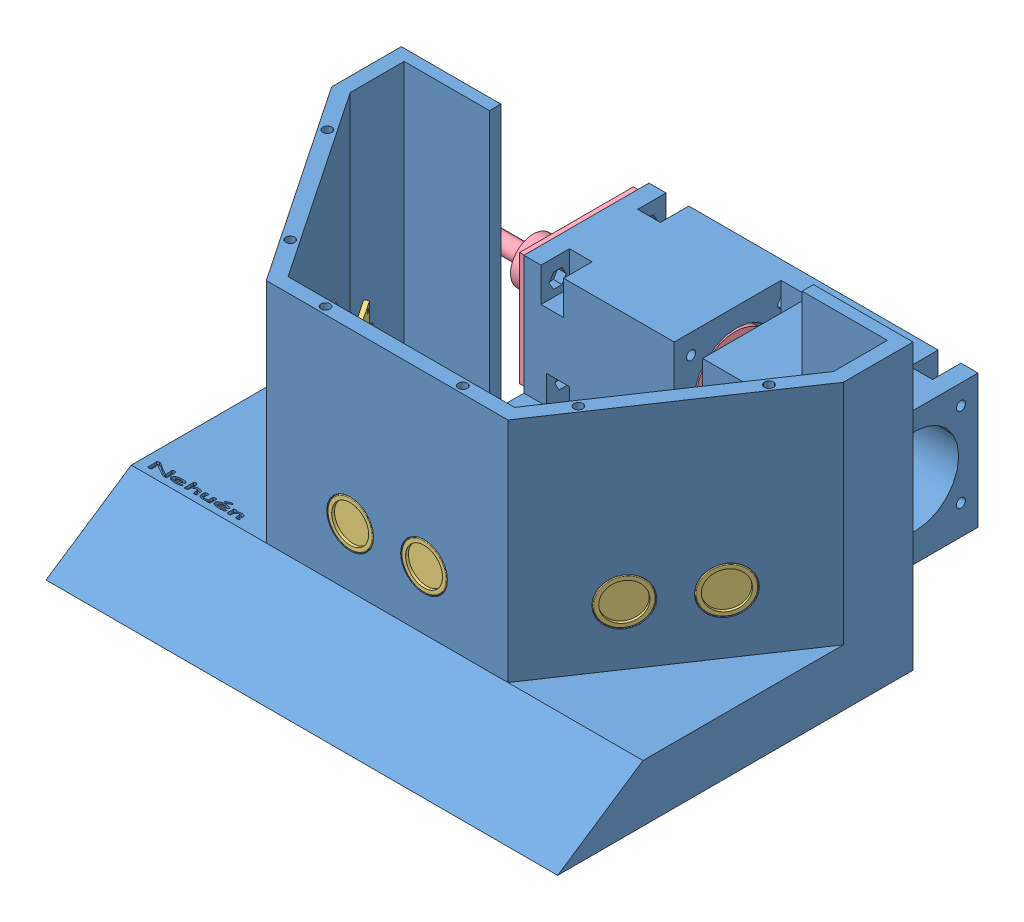
SolidWorks assembly Assem del sumo 2.0, configuration Default. Lengths in mm.
Overall size (186.62 100 180).
7 component instances, 4 part files, 13 mates.
Components (placement in the parent):
- SUMO 3.0-1: SUMO 3.0 [Default] at (66.1854 100.2215 134.4233) size (180 100 180)
- CNY70.step-1: CNY70.step [Default] at (7.7782 59.346 269.6233) x (1 0 0) z (0 0 -1) size (7 11.75 7)
- Sensor ultrasonico (1).step-1: Sensor ultrasonico (1).step [Default] at (79.2782 93.946 270.9233) x (-1 0 0) z (0 0 1) size (45 26.6 18)
- Sensor ultrasonico (1).step-2: Sensor ultrasonico (1).step [Default] at (134.3329 93.946 241.6345) x (-0.558824 0 0.829287) z (0.829287 0 0.558824) size (45 26.6 18)
- Sensor ultrasonico (1).step-3: Sensor ultrasonico (1).step [Default] at (24.2236 93.946 241.6345) x (-0.558824 0 -0.829287) z (-0.829287 0 0.558824) size (45 26.6 18)
- CNY70.step-2: CNY70.step [Default] at (150.7782 59.346 269.0233) x (1 0 0) z (0 0 -1) size (7 11.75 7)
- Motor ignis MR06B para sumo.step-1: Motor ignis MR06B para sumo.step [Default] at (-17.3433 78.446 156.4233) x (0 -1 0) z (1 0 0) size (40 40 93)
Mates (geometry in assembly coordinates):
- Coincident1: coincident: line of SUMO 3.0-1 through (11.6782 53.346 273.1233) axis (0 0 -1); plane of CNY70.step-1 through (4.2782 53.346 273.1233) normal (0 -1 0)
- Coincident2: coincident anti-aligned: plane of SUMO 3.0-1 through (4.2782 32.346 273.1233) normal (0 0 -1); plane of CNY70.step-1 through (11.2782 53.346 273.1233) normal (0 0 1)
- Coincident3: coincident anti-aligned: plane of SUMO 3.0-1 through (4.2782 32.346 265.7233) normal (1 0 0); plane of CNY70.step-1 through (4.2782 53.346 266.1233) normal (-1 0 0)
- Concentric1: concentric anti-aligned: cylinder of SUMO 3.0-1 through (92.2782 93.946 202.4233) axis (0 0 1) radius 8.25; cylinder of Sensor ultrasonico (1).step-1 through (92.2782 93.946 284.4233) axis (0 0 -1) radius 8
- Coincident4: coincident aligned: circle of SUMO 3.0-1; plane of Sensor ultrasonico (1).step-1 through (92.2782 93.946 284.4233) normal (0 0 1)
- Concentric2: concentric anti-aligned: cylinder of SUMO 3.0-1 through (84.7914 93.946 192.5744) axis (0.829287 0 0.558824) radius 8.25; cylinder of Sensor ultrasonico (1).step-2 through (152.7929 93.946 238.3979) axis (-0.829287 0 -0.558824) radius 8
- Coincident5: coincident aligned: circle of SUMO 3.0-1; plane of Sensor ultrasonico (1).step-2 through (152.7929 93.946 238.3979) normal (0.829287 0 0.558824)
- Concentric3: concentric anti-aligned: cylinder of SUMO 3.0-1 through (88.2944 93.946 214.1359) axis (-0.829287 0 0.558824) radius 8.25; cylinder of Sensor ultrasonico (1).step-3 through (20.2929 93.946 259.9594) axis (0.829287 0 -0.558824) radius 8
- Coincident6: coincident aligned: circle of SUMO 3.0-1; plane of Sensor ultrasonico (1).step-3 through (20.2929 93.946 259.9594) normal (-0.829287 0 0.558824)
- Coincident7: coincident anti-aligned: plane of SUMO 3.0-1 through (154.2782 32.346 265.7233) normal (-1 0 0); plane of CNY70.step-2 through (154.2782 53.346 265.5233) normal (1 0 0)
- Coincident9: coincident anti-aligned: line of SUMO 3.0-1 through (154.2782 53.346 265.7233) axis (-1 0 0); line of CNY70.step-2 through (147.4782 53.346 265.7233) axis (1 0 0)
- Concentric4: concentric aligned: cylinder of SUMO 3.0-1 through (-11.8518 78.446 156.4233) axis (1 0 0) radius 15.2; cylinder of Motor ignis MR06B para sumo.step-1 through (20.9067 78.446 156.4233) axis (1 0 0) radius 15
- Parallel1: parallel anti-aligned: line of SUMO 3.0-1 through (21.4082 53.346 189.4233) axis (0 0 -1); line of Motor ignis MR06B para sumo.step-1 through (17.9067 58.446 136.4233) axis (0 0 1)
